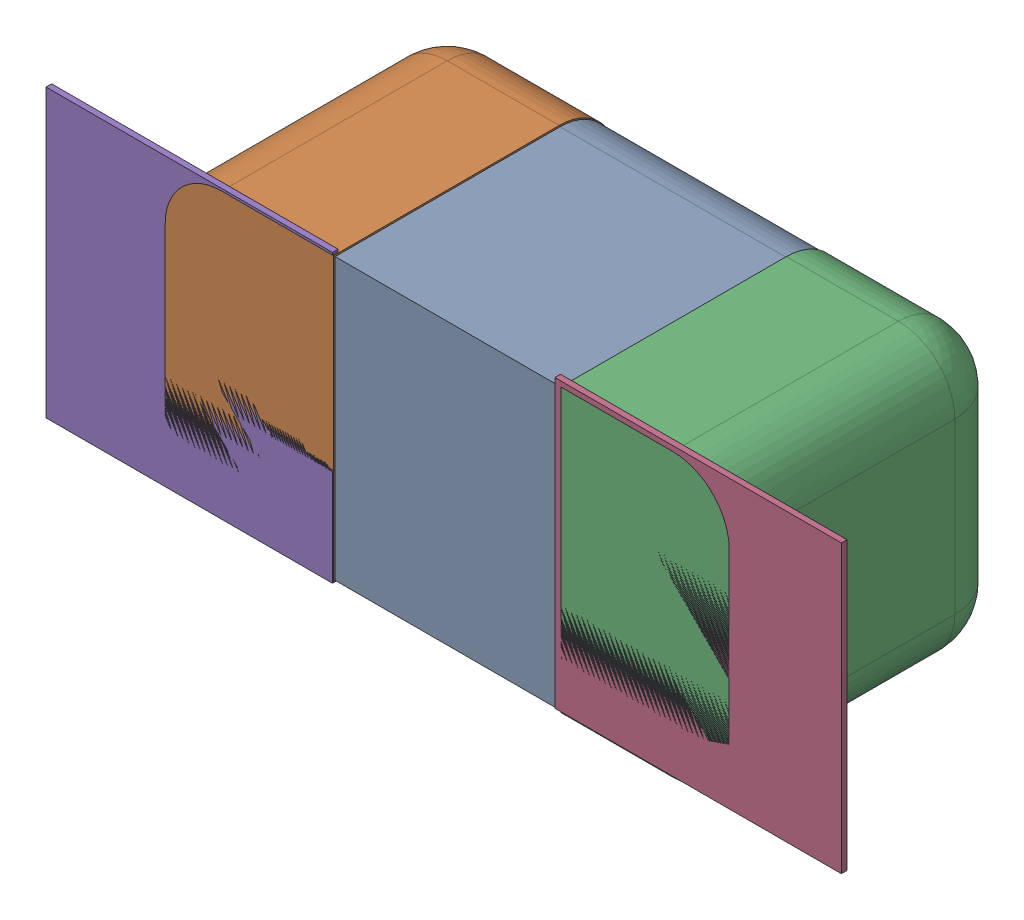
SolidWorks assembly C28, configuration Défaut. Lengths in mm.
Overall size (1.41 0.51 0.5).
8 component instances, 4 part files, 0 mates.
Components (placement in the parent):
- 5458962032-1: 5458962032 [Défaut] at (18.0848 -32.8168 -2.0818) x (1 0 0) z (0 1 0) size (1 0.5 0.5)
  - Open CASCADE STEP translator 7.5 2.80.1.1-1: Open CASCADE STEP translator 7.5 2.80.1.1 [Défaut] at origin size (0.4 0.5 0.5)
  - Open CASCADE STEP translator 7.5 2.80.1.2-1: Open CASCADE STEP translator 7.5 2.80.1.2 [Défaut] at origin size (0.3 0.5 0.5)
  - Open CASCADE STEP translator 7.5 2.80.1.3-1: Open CASCADE STEP translator 7.5 2.80.1.3 [Défaut] at origin size (0.3 0.5 0.5)
- 6504207776-1: 6504207776 [Défaut] at (18.5298 -32.8116 -2.0918) size (0.51 0.51 0.01)
  - Extruded-1: Extruded [Défaut] at origin size (0.51 0.51 0.01)
- 6504207776-2: 6504207776 [Défaut] at (17.6275 -32.8168 -2.0918) size (0.51 0.51 0.01)
  - Extruded-1: Extruded [Défaut] at origin size (0.51 0.51 0.01)
